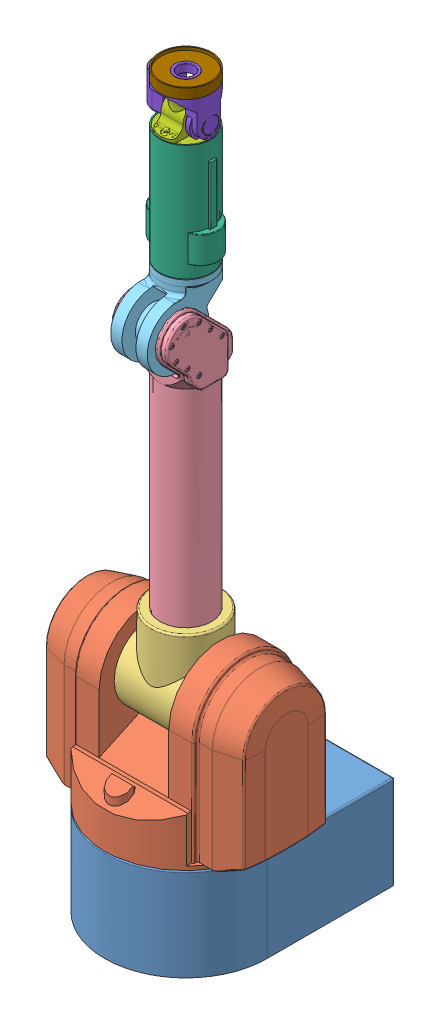
SolidWorks assembly wam, configuration zeroed. Lengths in mm.
Overall size (347.6 1260.42 360).
9 component instances, 9 part files, 14 mates.
Components (placement in the parent):
- B2123_2-1: B2123_2 [Default] at (-45.2708 -95.0327 74.1018) size (280 160 360)
- B2124_2-1: B2124_2 [Default] at (-45.2708 250.9673 74.1018) x (0 0 1) z (-1 0 0) size (280 275.48 347.6)
- B2125_2-1: B2125_2 [Default] at (-45.2708 250.9673 74.1018) x (-1 0 0) z (0 0 -1) size (120 172.5 127)
- B2126_2-1: B2126_2 [Default] at (-45.2708 250.9673 74.1018) x (-1 0 0) z (0 0 -1) size (96.33 590 129.5)
- B2127_2-1: B2127_2 [Default] at (-45.2708 800.9673 119.1018) x (1 0 0) z (0 1 0) size (88.99 142.5 131.3)
- B2571-1: B2571 [Default] at (-45.2708 873.9673 74.1018) x (-1 0 0) z (0 0 -1) size (111.5 205.8 89)
- B3308-1: B3308 [Default] at (-45.2708 1100.4773 74.1018) x (-1 0 0) z (0 0 -1) size (85 52.32 85)
- B2573_2-1: B2573_2 [Default] at (-45.2708 1148.4273 74.1018) size (103.08 85.22 88.9)
- B2574-1: B2574 [Default] at (-45.2708 1154.4273 74.1018) x (0 0 -1) z (1 0 0) size (89 16.96 89)
Mates (geometry in assembly coordinates):
- Coincident30: coordinate: point of B2123_2-1; point of B2124_2-1
- Coincident4: coincident anti-aligned: line of B2123_2-1 through (-45.2708 25.1047 74.1018) axis (0 1 0); line of B2124_2-1 through (-45.2708 386.5901 74.1018) axis (0 -1 0)
- Coincident31: coordinate: point of B2124_2-1; point of B2125_2-1
- Coincident8: coincident anti-aligned: line of B2124_2-1 through (227.3092 250.9673 74.1018) axis (-1 0 0); line of B2125_2-1 through (-105.2708 250.9673 74.1018) axis (1 0 0)
- Coincident32: coordinate: point of B2125_2-1; point of B2126_2-1
- Coincident12: coincident anti-aligned: line of B2125_2-1 through (-45.2708 200.8511 74.1018) axis (0 1 0); line of B2126_2-1 through (-45.2708 531.4674 74.1018) axis (0 -1 0)
- Coincident33: coordinate: point of B2126_2-1; point of B2127_2-1
- Coincident16: coincident aligned: line of B2126_2-1 through (-18.2727 800.9673 119.1018) axis (-1 0 0); line of B2127_2-1 through (5.2029 800.9673 119.1018) axis (-1 0 0)
- Coincident19: coordinate: point of B2127_2-1; point of B2571-1
- Coincident34: coordinate: point of B2571-1; point of B3308-1
- Coincident22: coincident anti-aligned: line of B2571-1 through (-45.2708 873.9282 74.1018) axis (0 1 0); line of B3308-1 through (-45.2708 1119.4773 74.1018) axis (0 -1 0)
- Coincident35: coordinate: point of B3308-1; point of B2573_2-1
- Coincident26: coincident anti-aligned: line of B3308-1 through (-10.7011 1100.4773 74.1018) axis (-1 0 0); line of B2573_2-1 through (-91.9327 1100.4773 74.1018) axis (1 0 0)
- Coincident29: coordinate: point of B2573_2-1; point of B2574-1
